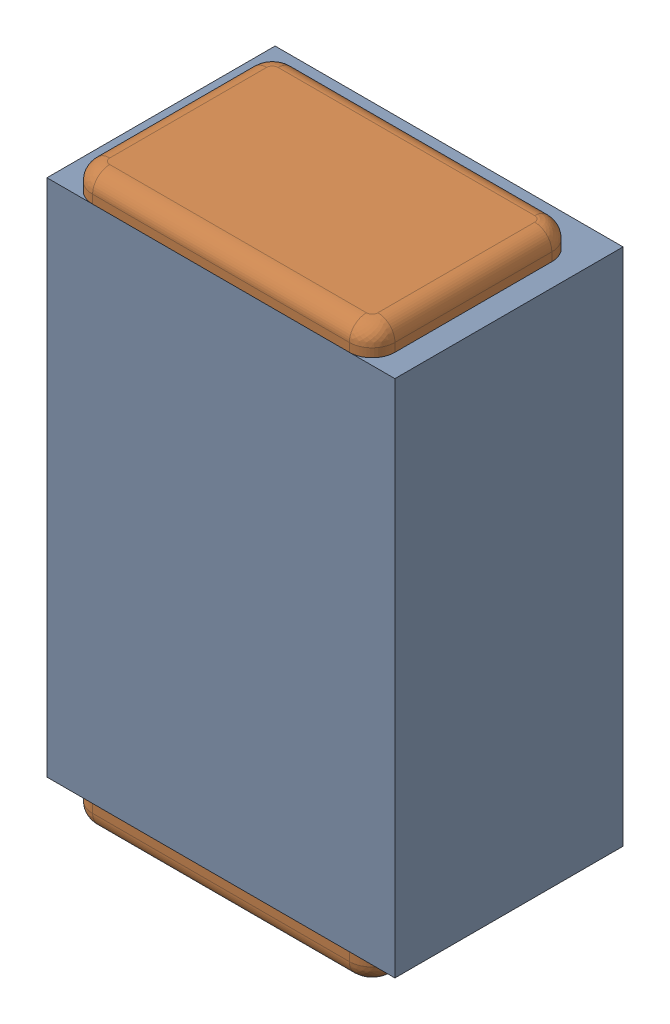
SolidWorks assembly C28, configuration Default. Lengths in mm.
Overall size (0.61 1 0.4).
3 component instances, 2 part files, 0 mates.
Components (placement in the parent):
- 1088881848-1: 1088881848 [Default] at (15 36.9 -2.044) size (0.61 0.91 0.4)
  - Extruded-1-1: Extruded-1 [Default] at origin size (0.61 0.91 0.4)
- C0402-1: C0402 [Default] at (15.0001 36.9001 -1.644) x (0 1 0) z (-1 0 0) size (1 0.36 0.54)
